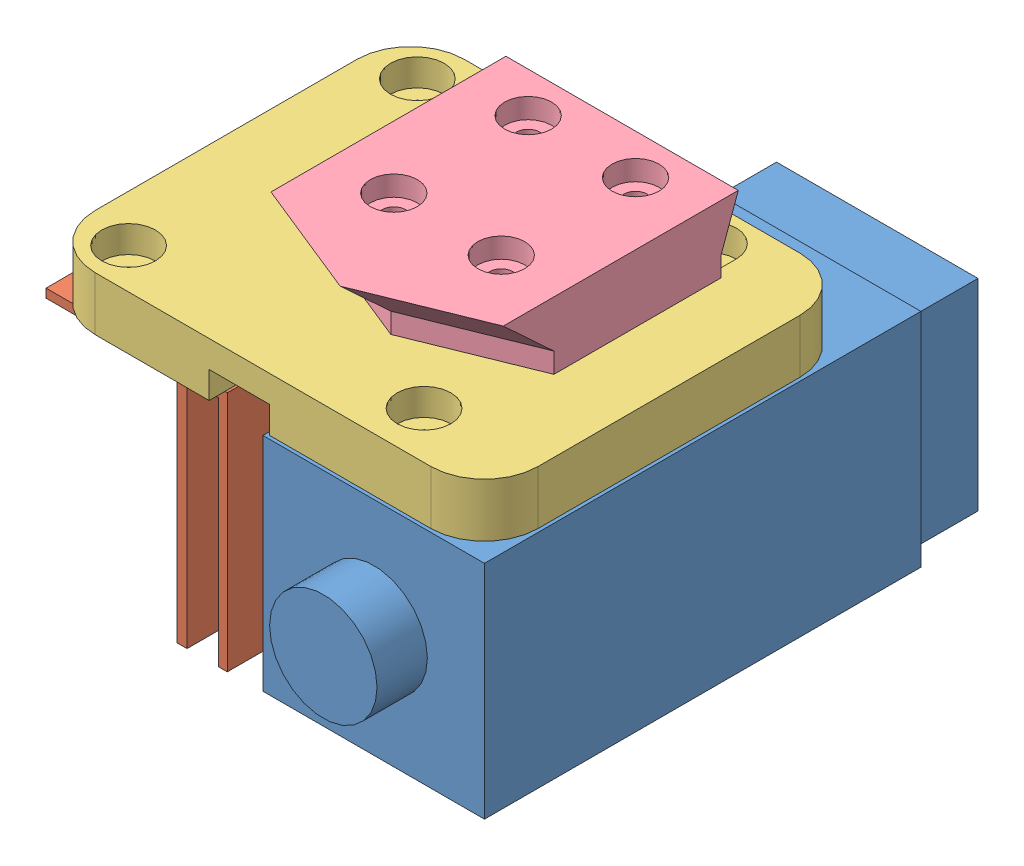
SolidWorks assembly #laser tool, configuration Valor predeterminado. Lengths in mm.
Overall size (68.15 54 82.5).
4 component instances, 4 part files, 9 mates.
Components (placement in the parent):
- laser 5.5w-1: laser 5.5w [Valor predeterminado] at (-55.5935 -14.6395 39.8498) size (33 33 82.5)
- laser driver-1: laser driver [Valor predeterminado] at (-80.2435 1.8605 101.9998) x (0 -1 0) z (0 0 -1) size (36 27 50)
- laser holder-1: laser holder [Valor predeterminado] at (-105.5935 9.8605 104.3498) x (1 0 0) z (0 0 -1) size (66 8 55)
- Scraper_tool-1: Scraper_tool [Valor predeterminado] at (-67.5935 19.8605 71.3498) x (-1 0 0) z (0 -1 0) size (34.6 42 10)
Mates (geometry in assembly coordinates):
- Coincidente1: coincident anti-aligned: plane of laser 5.5w-1 through (-72.0935 1.8605 104.8498) normal (0 1 0); plane of laser holder-1 through (-105.5935 1.8605 104.3498) normal (0 -1 0)
- Concêntrico2: concentric aligned: cylinder of laser 5.5w-1 through (-55.5935 -5.6395 97.3498) axis (0 1 0) radius 1.5; cylinder of laser holder-1 through (-55.5935 5.8605 97.3498) axis (0 1 0) radius 1.75
- Ranhura2: slot aligned: cylinder of laser holder-1 through (-55.5935 5.8605 57.8498) axis (0 1 0) radius 1.75; cylinder of laser 5.5w-1 through (-55.5935 -5.6395 56.3498) axis (0 1 0) radius 1.5; cylinder of laser holder-1 through (-55.5935 5.8605 54.8498) axis (0 1 0) radius 1.75
- Paralelo2: parallel anti-aligned: plane of laser 5.5w-1 through (-72.0935 1.8605 104.8498) normal (-1 0 0); plane of laser driver-1 through (-80.2435 -34.1395 51.9998) normal (1 0 0)
- Coincidente3: coincident anti-aligned: plane of laser driver-1 through (-80.2435 1.8605 51.9998) normal (0 1 0); plane of laser holder-1 through (-105.5935 1.8605 104.3498) normal (0 -1 0)
- Concêntrico6: concentric aligned: cylinder of laser driver-1 through (-98.5935 -48.1395 55.3498) axis (0 1 0) radius 1.65; cylinder of laser holder-1 through (-98.5935 5.8605 55.3498) axis (0 1 0) radius 1.75
- Concêntrico7: concentric anti-aligned: cylinder of laser holder-1 through (-75.5935 5.8605 81.8498) axis (0 1 0) radius 1.75; cylinder of Scraper_tool-1 through (-75.5935 19.8605 81.8498) axis (0 -1 0) radius 1.75
- Concêntrico8: concentric anti-aligned: cylinder of laser holder-1 through (-75.5935 5.8605 61.8498) axis (0 1 0) radius 1.75; cylinder of Scraper_tool-1 through (-75.5935 19.8605 61.8498) axis (0 -1 0) radius 1.75
- Coincidente4: coincident anti-aligned: plane of laser holder-1 through (-105.5935 9.8605 49.3498) normal (0 1 0); plane of Scraper_tool-1 through (-67.5935 9.8605 71.3498) normal (0 -1 0)
